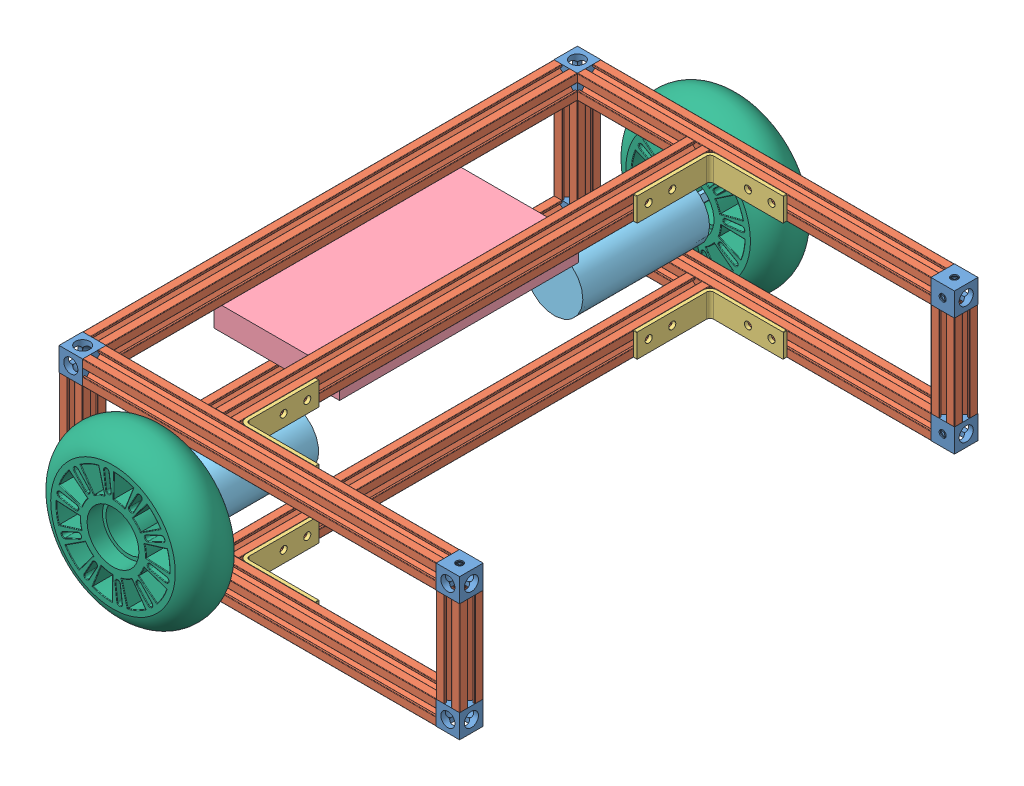
SolidWorks assembly Assemblage1, configuration Default. Lengths in mm.
Overall size (170 86.9 267.12).
29 component instances, 6 part files, 84 mates.
Components (placement in the parent):
- corner_cube-1: corner_cube [Défaut] at (-80 25 105) x (0 0 1) z (-1 0 0) size (10 10 10)
- corner_cube-2: corner_cube [Défaut] at (-80 25 -105) x (-1 0 0) z (0 0 -1) size (10 10 10)
- pièce_tige_toutes_les_configurations-1: pièce_tige_toutes_les_configurations [200mm] at (-80 25 0) size (10 10 200)
- pièce_tige_toutes_les_configurations-3: pièce_tige_toutes_les_configurations [150mm] at (0 25 105) x (0 0 -1) z (1 0 0) size (10 10 150)
- pièce_tige_toutes_les_configurations-4: pièce_tige_toutes_les_configurations [150mm] at (0 25 -105) x (0 0 -1) z (1 0 0) size (10 10 150)
- pièce_tige_toutes_les_configurations-5: pièce_tige_toutes_les_configurations [200mm] at (-23.7 25 0) size (10 10 200)
- support angle droit coin-1: support angle droit coin [Défaut] at (-17.95 20 98.6965) x (0 1 0) z (1 0 0) size (10 32.55 32.55)
- support angle droit coin-2: support angle droit coin [Défaut] at (-17.3965 20 -99.25) x (0 1 0) z (0 0 1) size (10 32.55 32.55)
- pièce_tige_toutes_les_configurations-6: pièce_tige_toutes_les_configurations [150mm] at (0 -25 -105) x (0 0 -1) z (1 0 0) size (10 10 150)
- corner_cube-3: corner_cube [Défaut] at (-80 -25 -105) x (0 -1 0) z (0 0 -1) size (10 10 10)
- pièce_tige_toutes_les_configurations-7: pièce_tige_toutes_les_configurations [40mm] at (-80 0 105) x (0 0 -1) z (0 -1 0) size (10 10 40)
- pièce_tige_toutes_les_configurations-8: pièce_tige_toutes_les_configurations [40mm] at (-80 0 -105) x (0 0 -1) z (0 -1 0) size (10 10 40)
- corner_cube-4: corner_cube [Défaut] at (-80 -25 105) x (0 0 1) z (0 -1 0) size (10 10 10)
- pièce_tige_toutes_les_configurations-9: pièce_tige_toutes_les_configurations [200mm] at (-80 -25 0) size (10 10 200)
- pièce_tige_toutes_les_configurations-10: pièce_tige_toutes_les_configurations [150mm] at (0 -25 105) x (0 0 -1) z (1 0 0) size (10 10 150)
- pièce_tige_toutes_les_configurations-11: pièce_tige_toutes_les_configurations [40mm] at (80 0 105) x (1 0 0) z (0 1 0) size (10 10 40)
- corner_cube-5: corner_cube [Défaut] at (80 -25 105) x (1 0 0) z (0 -1 0) size (10 10 10)
- corner_cube-6: corner_cube [Défaut] at (80 25 105) x (1 0 0) z (0 -1 0) size (10 10 10)
- pièce_tige_toutes_les_configurations-12: pièce_tige_toutes_les_configurations [40mm] at (80 0 -105) x (0 0 -1) z (0 1 0) size (10 10 40)
- corner_cube-7: corner_cube [Défaut] at (80 25 -105) x (0 0 -1) z (0 -1 0) size (10 10 10)
- corner_cube-8: corner_cube [Défaut] at (80 -25 -105) x (0 0 -1) z (0 -1 0) size (10 10 10)
- pièce_tige_toutes_les_configurations-13: pièce_tige_toutes_les_configurations [200mm] at (-23.7 -25 0) size (10 10 200)
- support angle droit coin-3: support angle droit coin [Défaut] at (-17.95 -30 98.6965) x (0 1 0) z (1 0 0) size (10 32.55 32.55)
- support angle droit coin-4: support angle droit coin [Défaut] at (-17.3965 -30 -99.25) x (0 1 0) z (0 0 1) size (10 32.55 32.55)
- Volume carte arduino méga-2: Volume carte arduino méga [Default] at (-51.85 10 0) x (0 0 1) z (0 1 0) size (101.52 53.3 10)
- taille moteur-3: taille moteur [Default] at (-40.9 -7.8 82.9944) x (0.583615 -0.81203 0) z (0 0 1) size (24.4 24.4 66.3)
- taille moteur-4: taille moteur [Default] at (-40.9 -7.8 -82.9011) x (0.48092 -0.876764 0) z (0 0 -1) size (24.4 24.4 66.3)
- Roue2-1: Roue2 [Défaut] at (-40.9 -7.8 119.7073) x (0 0 1) z (-0.999844 0.017684 0) size (23.04 70 70)
- Roue2-2: Roue2 [Défaut] at (-40.9 -7.8 -124.3725) x (0 0 1) z (-0.959433 -0.281938 0) size (23.04 70 70)
Mates (geometry in assembly coordinates):
- Coïncidente1: coincident anti-aligned: plane of corner_cube-1 through (-75 20 100) normal (0 0 -1); plane of pièce_tige_toutes_les_configurations-1 through (-85 20 100) normal (0 0 1)
- Coïncidente2: coincident anti-aligned: plane of corner_cube-2 through (-85 20 -100) normal (0 0 1); plane of pièce_tige_toutes_les_configurations-1 through (-75 20 -100) normal (0 0 -1)
- Coïncidente3: coincident aligned: plane of corner_cube-1 through (-75 20 110) normal (1 0 0); plane of pièce_tige_toutes_les_configurations-1 through (-75 20 100) normal (1 0 0)
- Coïncidente4: coincident aligned: plane of corner_cube-2 through (-75 20 -100) normal (1 0 0); plane of pièce_tige_toutes_les_configurations-1 through (-75 20 100) normal (1 0 0)
- Coïncidente5: coincident aligned: plane of corner_cube-2 through (-80 20 -105) normal (0 -1 0); plane of pièce_tige_toutes_les_configurations-1 through (-80 20 0) normal (0 -1 0)
- Coïncidente6: coincident aligned: plane of corner_cube-1 through (-80 20 105) normal (0 -1 0); plane of pièce_tige_toutes_les_configurations-1 through (-80 20 0) normal (0 -1 0)
- Coïncidente7: coincident anti-aligned: plane of corner_cube-1 through (-75 20 110) normal (1 0 0); plane of pièce_tige_toutes_les_configurations-3 through (-75 20 100) normal (-1 0 0)
- Coïncidente8: coincident aligned: plane of corner_cube-1 through (-85 20 110) normal (0 0 1); plane of pièce_tige_toutes_les_configurations-3 through (-75 20 110) normal (0 0 1)
- Coïncidente9: coincident aligned: plane of corner_cube-1 through (-80 30 105) normal (0 1 0); plane of pièce_tige_toutes_les_configurations-3 through (0 30 105) normal (0 1 0)
- Coïncidente10: coincident anti-aligned: plane of corner_cube-2 through (-75 20 -100) normal (1 0 0); plane of pièce_tige_toutes_les_configurations-4 through (-75 20 -110) normal (-1 0 0)
- Coïncidente11: coincident aligned: plane of corner_cube-2 through (-75 20 -110) normal (0 0 -1); plane of pièce_tige_toutes_les_configurations-4 through (75 20 -110) normal (0 0 -1)
- Coïncidente12: coincident aligned: plane of corner_cube-2 through (-80 30 -105) normal (0 1 0); plane of pièce_tige_toutes_les_configurations-4 through (0 30 -105) normal (0 1 0)
- Coïncidente13: coincident aligned: plane of pièce_tige_toutes_les_configurations-1 through (-80 25 0) normal (0 0 1); plane of assembly through (0 0 0) normal (0 0 1)
- Coïncidente14: coincident anti-aligned: plane of pièce_tige_toutes_les_configurations-4 through (-75 20 -100) normal (0 0 1); plane of pièce_tige_toutes_les_configurations-5 through (-18.7 20 -100) normal (0 0 -1)
- Coïncidente15: coincident anti-aligned: plane of pièce_tige_toutes_les_configurations-3 through (75 20 100) normal (0 0 -1); plane of pièce_tige_toutes_les_configurations-5 through (-28.7 20 100) normal (0 0 1)
- Coïncidente16: coincident aligned: plane of pièce_tige_toutes_les_configurations-3 through (0 30 105) normal (0 1 0); plane of pièce_tige_toutes_les_configurations-5 through (-23.7 30 0) normal (0 1 0)
- Coïncidente17: coincident anti-aligned: plane of pièce_tige_toutes_les_configurations-5 through (-18.7 20 100) normal (1 0 0); plane of support angle droit coin-1 through (-18.7 20 67.4465) normal (-1 0 0)
- Coïncidente18: coincident anti-aligned: plane of pièce_tige_toutes_les_configurations-3 through (75 20 100) normal (0 0 -1); plane of support angle droit coin-1 through (-18.7 20 100) normal (0 0 1)
- Coïncidente19: coincident aligned: plane of pièce_tige_toutes_les_configurations-5 through (-23.7 30 0) normal (0 1 0); plane of support angle droit coin-1 through (-17.95 30 98.6965) normal (0 1 0)
- Coïncidente20: coincident aligned: plane of pièce_tige_toutes_les_configurations-5 through (-23.7 20 0) normal (0 -1 0); plane of support angle droit coin-1 through (-17.95 20 98.6965) normal (0 -1 0)
- Coïncidente21: coincident anti-aligned: plane of pièce_tige_toutes_les_configurations-4 through (-75 20 -100) normal (0 0 1); plane of support angle droit coin-2 through (13.8535 20 -100) normal (0 0 -1)
- Coïncidente22: coincident anti-aligned: plane of pièce_tige_toutes_les_configurations-5 through (-18.7 20 100) normal (1 0 0); plane of support angle droit coin-2 through (-18.7 20 -100) normal (-1 0 0)
- Coïncidente23: coincident aligned: plane of pièce_tige_toutes_les_configurations-4 through (0 30 -105) normal (0 1 0); plane of support angle droit coin-2 through (-17.3965 30 -99.25) normal (0 1 0)
- Coïncidente31: coincident anti-aligned: plane of corner_cube-1 through (-80 20 105) normal (0 -1 0); plane of pièce_tige_toutes_les_configurations-7 through (-85 20 100) normal (0 1 0)
- Coïncidente32: coincident anti-aligned: plane of corner_cube-2 through (-80 20 -105) normal (0 -1 0); plane of pièce_tige_toutes_les_configurations-8 through (-85 20 -110) normal (0 1 0)
- Coïncidente33: coincident aligned: plane of corner_cube-2 through (-75 20 -110) normal (0 0 -1); plane of pièce_tige_toutes_les_configurations-8 through (-85 -20 -110) normal (0 0 -1)
- Coïncidente34: coincident aligned: plane of corner_cube-2 through (-85 20 -110) normal (-1 0 0); plane of pièce_tige_toutes_les_configurations-8 through (-85 0 -105) normal (-1 0 0)
- Coïncidente35: coincident aligned: plane of corner_cube-1 through (-85 20 110) normal (0 0 1); plane of pièce_tige_toutes_les_configurations-7 through (-85 20 110) normal (0 0 1)
- Coïncidente36: coincident aligned: plane of corner_cube-1 through (-85 20 100) normal (-1 0 0); plane of pièce_tige_toutes_les_configurations-7 through (-85 0 105) normal (-1 0 0)
- Coïncidente37: coincident anti-aligned: plane of pièce_tige_toutes_les_configurations-7 through (-85 -20 110) normal (0 -1 0); plane of corner_cube-4 through (-75 -20 110) normal (0 1 0)
- Coïncidente40: coincident anti-aligned: plane of corner_cube-3 through (-75 -20 -100) normal (0 1 0); plane of pièce_tige_toutes_les_configurations-8 through (-85 -20 -100) normal (0 -1 0)
- Coïncidente41: coincident anti-aligned: plane of pièce_tige_toutes_les_configurations-6 through (-75 -30 -110) normal (-1 0 0); plane of corner_cube-3 through (-75 -25 -105) normal (1 0 0)
- Coïncidente42: coincident aligned: plane of corner_cube-3 through (-75 -20 -110) normal (0 0 -1); plane of pièce_tige_toutes_les_configurations-8 through (-85 -20 -110) normal (0 0 -1)
- Coïncidente43: coincident aligned: plane of pièce_tige_toutes_les_configurations-6 through (75 -30 -110) normal (0 0 -1); plane of corner_cube-3 through (-75 -20 -110) normal (0 0 -1)
- Coïncidente44: coincident aligned: plane of corner_cube-3 through (-75 -25 -105) normal (1 0 0); plane of pièce_tige_toutes_les_configurations-8 through (-75 0 -105) normal (1 0 0)
- Coïncidente45: coincident aligned: plane of pièce_tige_toutes_les_configurations-6 through (0 -30 -105) normal (0 -1 0); plane of corner_cube-3 through (-75 -30 -110) normal (0 -1 0)
- Coïncidente47: coincident anti-aligned: plane of corner_cube-3 through (-75 -30 -100) normal (0 0 1); plane of pièce_tige_toutes_les_configurations-9 through (-75 -30 -100) normal (0 0 -1)
- Coïncidente48: coincident aligned: plane of corner_cube-3 through (-85 -25 -105) normal (-1 0 0); plane of pièce_tige_toutes_les_configurations-9 through (-85 -30 -100) normal (-1 0 0)
- Coïncidente49: coincident aligned: plane of corner_cube-4 through (-75 -30 100) normal (0 -1 0); plane of pièce_tige_toutes_les_configurations-9 through (-80 -30 0) normal (0 -1 0)
- Coïncidente51: coincident aligned: plane of corner_cube-4 through (-75 -30 100) normal (0 -1 0); plane of pièce_tige_toutes_les_configurations-10 through (0 -30 105) normal (0 -1 0)
- Coïncidente56: coincident aligned: plane of pièce_tige_toutes_les_configurations-11 through (75 -20 110) normal (-1 0 0); plane of corner_cube-6 through (75 30 100) normal (-1 0 0)
- Coïncidente57: coincident aligned: plane of pièce_tige_toutes_les_configurations-11 through (80 0 110) normal (0 0 1); plane of corner_cube-6 through (80 25 110) normal (0 0 1)
- Coïncidente59: coincident aligned: plane of pièce_tige_toutes_les_configurations-10 through (0 -20 105) normal (0 1 0); plane of corner_cube-5 through (85 -20 100) normal (0 1 0)
- Coïncidente63: coincident anti-aligned: plane of pièce_tige_toutes_les_configurations-11 through (75 20 110) normal (0 1 0); plane of corner_cube-6 through (75 20 100) normal (0 -1 0)
- Coïncidente64: coincident anti-aligned: plane of pièce_tige_toutes_les_configurations-11 through (85 -20 110) normal (0 -1 0); plane of corner_cube-5 through (85 -20 100) normal (0 1 0)
- Coïncidente65: coincident anti-aligned: plane of pièce_tige_toutes_les_configurations-12 through (85 -20 -110) normal (0 -1 0); plane of corner_cube-8 through (75 -20 -110) normal (0 1 0)
- Coïncidente66: coincident aligned: plane of pièce_tige_toutes_les_configurations-12 through (85 20 -110) normal (0 0 -1); plane of corner_cube-8 through (75 -30 -110) normal (0 0 -1)
- Coïncidente67: coincident aligned: plane of pièce_tige_toutes_les_configurations-12 through (85 0 -105) normal (1 0 0); plane of corner_cube-8 through (85 -25 -105) normal (1 0 0)
- Coïncidente68: coincident aligned: plane of pièce_tige_toutes_les_configurations-12 through (85 0 -105) normal (1 0 0); plane of corner_cube-7 through (85 25 -105) normal (1 0 0)
- Coïncidente69: coincident anti-aligned: plane of pièce_tige_toutes_les_configurations-12 through (85 20 -100) normal (0 1 0); plane of corner_cube-7 through (75 20 -100) normal (0 -1 0)
- Coïncidente70: coincident aligned: plane of pièce_tige_toutes_les_configurations-12 through (85 20 -110) normal (0 0 -1); plane of corner_cube-7 through (75 20 -110) normal (0 0 -1)
- Coïncidente71: coincident anti-aligned: plane of pièce_tige_toutes_les_configurations-4 through (75 20 -100) normal (1 0 0); plane of corner_cube-7 through (75 25 -105) normal (-1 0 0)
- Coïncidente72: coincident aligned: plane of pièce_tige_toutes_les_configurations-4 through (0 30 -105) normal (0 1 0); plane of corner_cube-7 through (75 30 -110) normal (0 1 0)
- Coïncidente73: coincident aligned: plane of pièce_tige_toutes_les_configurations-4 through (75 20 -110) normal (0 0 -1); plane of corner_cube-7 through (75 20 -110) normal (0 0 -1)
- Coïncidente74: coincident aligned: plane of pièce_tige_toutes_les_configurations-11 through (80 0 110) normal (0 0 1); plane of corner_cube-5 through (80 -25 110) normal (0 0 1)
- Coïncidente75: coincident anti-aligned: plane of pièce_tige_toutes_les_configurations-3 through (75 20 110) normal (1 0 0); plane of corner_cube-6 through (75 30 100) normal (-1 0 0)
- Coïncidente76: coincident aligned: plane of pièce_tige_toutes_les_configurations-3 through (-75 20 110) normal (0 0 1); plane of corner_cube-6 through (80 25 110) normal (0 0 1)
- Coïncidente77: coincident aligned: plane of pièce_tige_toutes_les_configurations-10 through (-75 -30 110) normal (0 0 1); plane of corner_cube-5 through (80 -25 110) normal (0 0 1)
- Coïncidente78: coincident aligned: plane of pièce_tige_toutes_les_configurations-11 through (85 20 110) normal (1 0 0); plane of corner_cube-5 through (85 -30 100) normal (1 0 0)
- Coïncidente79: coincident anti-aligned: plane of pièce_tige_toutes_les_configurations-6 through (-75 -30 -100) normal (0 0 1); plane of pièce_tige_toutes_les_configurations-13 through (-18.7 -30 -100) normal (0 0 -1)
- Coïncidente80: coincident anti-aligned: plane of pièce_tige_toutes_les_configurations-10 through (75 -30 100) normal (0 0 -1); plane of pièce_tige_toutes_les_configurations-13 through (-28.7 -30 100) normal (0 0 1)
- Coïncidente81: coincident aligned: plane of pièce_tige_toutes_les_configurations-10 through (0 -30 105) normal (0 -1 0); plane of pièce_tige_toutes_les_configurations-13 through (-23.7 -30 0) normal (0 -1 0)
- Coïncidente82: coincident aligned: plane of pièce_tige_toutes_les_configurations-6 through (0 -30 -105) normal (0 -1 0); plane of pièce_tige_toutes_les_configurations-13 through (-23.7 -30 0) normal (0 -1 0)
- Coïncidente83: coincident aligned: plane of pièce_tige_toutes_les_configurations-5 through (-18.7 20 100) normal (1 0 0); plane of pièce_tige_toutes_les_configurations-13 through (-18.7 -30 100) normal (1 0 0)
- Coïncidente84: coincident anti-aligned: plane of pièce_tige_toutes_les_configurations-13 through (-18.7 -30 100) normal (1 0 0); plane of support angle droit coin-3 through (-18.7 -30 67.4465) normal (-1 0 0)
- Coïncidente85: coincident anti-aligned: plane of pièce_tige_toutes_les_configurations-10 through (75 -30 100) normal (0 0 -1); plane of support angle droit coin-3 through (-18.7 -30 100) normal (0 0 1)
- Coïncidente86: coincident aligned: plane of pièce_tige_toutes_les_configurations-10 through (0 -20 105) normal (0 1 0); plane of support angle droit coin-3 through (-17.95 -20 98.6965) normal (0 1 0)
- Coïncidente87: coincident aligned: plane of pièce_tige_toutes_les_configurations-13 through (-23.7 -20 0) normal (0 1 0); plane of support angle droit coin-4 through (-17.3965 -20 -99.25) normal (0 1 0)
- Coïncidente88: coincident anti-aligned: plane of pièce_tige_toutes_les_configurations-13 through (-18.7 -30 100) normal (1 0 0); plane of support angle droit coin-4 through (-18.7 -30 -100) normal (-1 0 0)
- Coïncidente89: coincident anti-aligned: plane of pièce_tige_toutes_les_configurations-6 through (-75 -30 -100) normal (0 0 1); plane of support angle droit coin-4 through (13.8535 -30 -100) normal (0 0 -1)
- Coïncidente91: coincident aligned: plane of pièce_tige_toutes_les_configurations-6 through (0 -25 -105) normal (1 0 0); plane of assembly through (0 0 0) normal (1 0 0)
- Coïncidente92: coincident aligned: plane of pièce_tige_toutes_les_configurations-1 through (-80 25 0) normal (0 0 1); plane of assembly through (0 0 0) normal (0 0 1)
- Coïncidente93: coincident anti-aligned: plane of pièce_tige_toutes_les_configurations-8 through (-80 0 -105) normal (0 -1 0); plane of assembly through (0 0 0) normal (0 1 0)
- Coaxiale2: concentric anti-aligned: cylinder of taille moteur-3 through (-40.9 -7.8 109.8944) axis (0 0 -1) radius 12.2; cylinder of taille moteur-4 through (-40.9 -7.8 -109.8011) axis (0 0 1) radius 12.2
- Tangent3: tangent anti-aligned: plane of pièce_tige_toutes_les_configurations-5 through (-28.7 20 -100) normal (-1 0 0); cylinder of taille moteur-3 through (-40.9 -7.8 109.8944) axis (0 0 -1) radius 12.2
- Coïncidente101: coincident aligned: plane of pièce_tige_toutes_les_configurations-13 through (-25.2 -20 -100) normal (1 0 0); plane of Volume carte arduino méga-2 through (-25.2 20 -50.76) normal (1 0 0)
- Coïncidente102: coincident aligned: plane of pièce_tige_toutes_les_configurations-9 through (-78.5 -21 -100) normal (-1 0 0); plane of Volume carte arduino méga-2 through (-78.5 20 -50.76) normal (-1 0 0)
- Coïncidente103: coincident anti-aligned: plane of pièce_tige_toutes_les_configurations-5 through (-23.7 20 0) normal (0 -1 0); plane of Volume carte arduino méga-2 through (-51.85 20 0) normal (0 1 0)
- Coïncidente104: coincident aligned: plane of Volume carte arduino méga-2 through (-51.85 10 0) normal (0 0 1); plane of assembly through (0 0 0) normal (0 0 1)
- Tangent4: tangent anti-aligned: plane of pièce_tige_toutes_les_configurations-10 through (0 -20 105) normal (0 1 0); cylinder of taille moteur-3 through (-40.9 -7.8 109.8944) axis (0 0 -1) radius 12.2
- Coaxiale3: concentric anti-aligned: cylinder of taille moteur-3 through (-40.9 -7.8 109.8944) axis (0 0 -1) radius 12.2; cylinder of Roue2-1 through (-40.9 -7.8 107.7073) axis (0 0 1) radius 9.5
- Coïncidente105: coincident aligned: plane of corner_cube-4 through (-85 -25 105) normal (-1 0 0); plane of pièce_tige_toutes_les_configurations-9 through (-85 -30 -100) normal (-1 0 0)
- Coïncidente106: coincident aligned: plane of corner_cube-4 through (-75 -30 110) normal (0 0 1); plane of pièce_tige_toutes_les_configurations-10 through (-75 -30 110) normal (0 0 1)
- Coaxiale4: concentric aligned: cylinder of taille moteur-4 through (-40.9 -7.8 -122.3011) axis (0 0 1) radius 2; cylinder of Roue2-2 through (-40.9 -7.8 -136.3725) axis (0 0 1) radius 9.5
